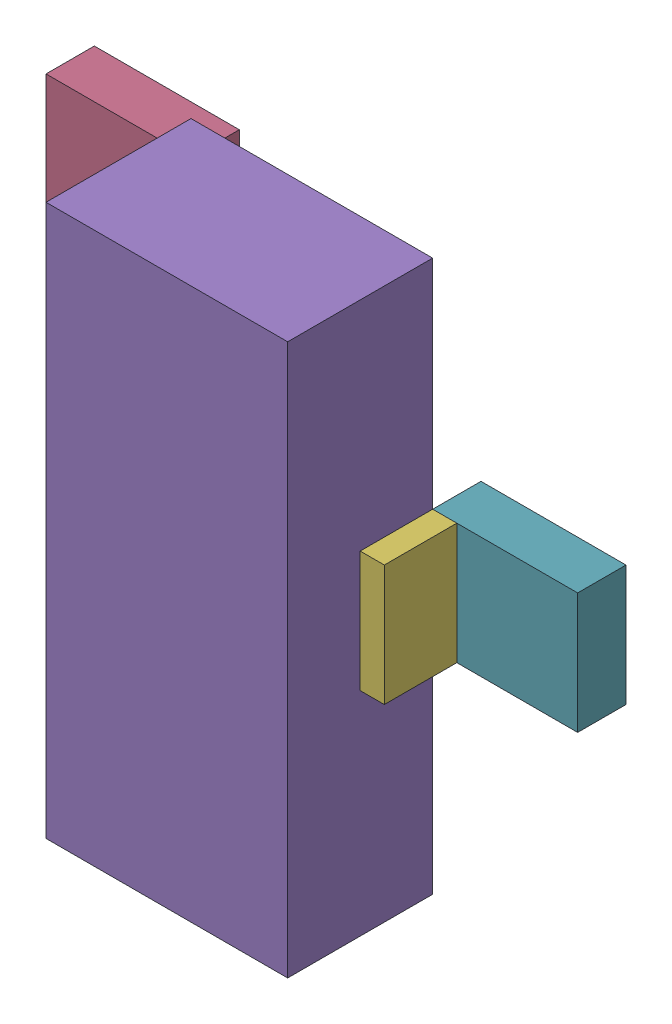
SolidWorks assembly Q9, configuration Default. Lengths in mm.
Overall size (2.79 2.9 1.02).
14 component instances, 3 part files, 0 mates.
Components (placement in the parent):
- 898052632-1: 898052632 [Default] at (39.339 12.5831 0.254) size (0.13 0.64 0.38)
  - Extruded_12-1: Extruded_12 [Default] at origin size (0.13 0.64 0.38)
- 898052496-1: 898052496 [Default] at (39.0215 12.5831 0) size (0.76 0.64 0.25)
  - Extruded_10-1: Extruded_10 [Default] at origin size (0.76 0.64 0.25)
- 898052632-2: 898052632 [Default] at (39.339 14.4881 0.254) size (0.13 0.64 0.38)
  - Extruded_12-1: Extruded_12 [Default] at origin size (0.13 0.64 0.38)
- 898052496-2: 898052496 [Default] at (39.0215 14.4881 0) size (0.76 0.64 0.25)
  - Extruded_10-1: Extruded_10 [Default] at origin size (0.76 0.64 0.25)
- 898052360-1: 898052360 [Default] at (40.0375 13.5356 0.254) size (1.27 2.9 0.76)
  - Extruded_11-1: Extruded_11 [Default] at origin size (1.27 2.9 0.76)
- 898052632-3: 898052632 [Default] at (40.736 13.5229 0.254) size (0.13 0.64 0.38)
  - Extruded_12-1: Extruded_12 [Default] at origin size (0.13 0.64 0.38)
- 898052496-3: 898052496 [Default] at (41.0535 13.5229 0) size (0.76 0.64 0.25)
  - Extruded_10-1: Extruded_10 [Default] at origin size (0.76 0.64 0.25)
